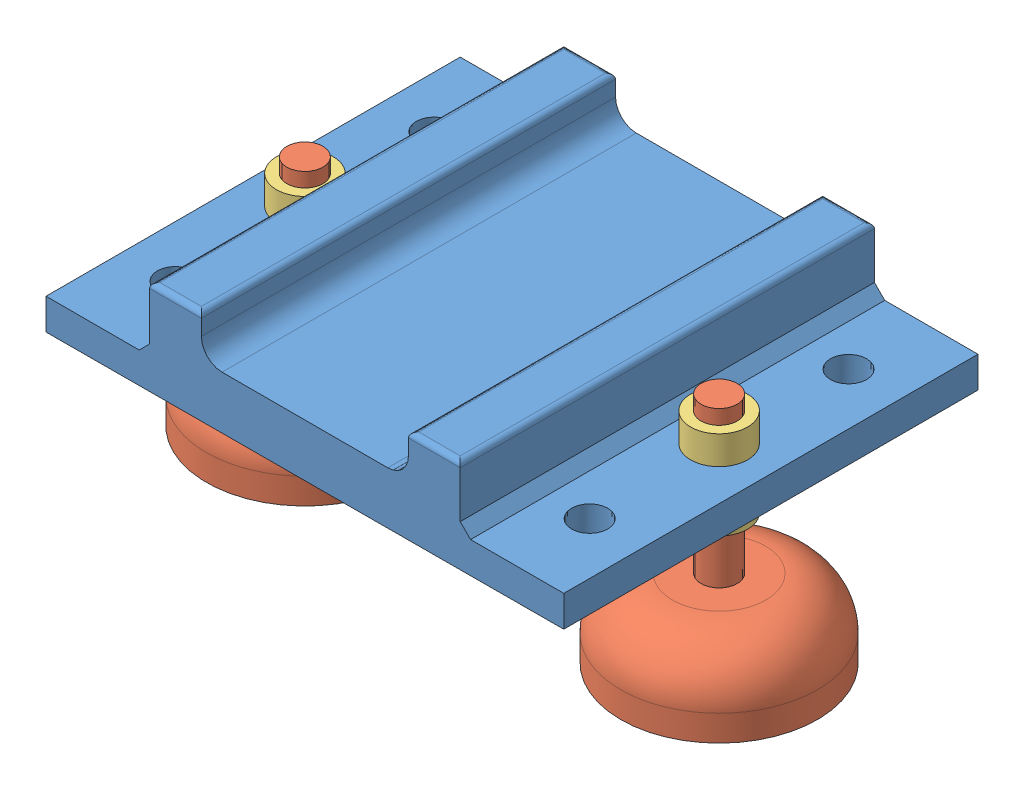
SolidWorks assembly Assemblage1, configuration Défaut. Lengths in mm.
Overall size (129.85 48.97 80).
7 component instances, 3 part files, 6 mates.
Components (placement in the parent):
- piece_maintient_entre_rail-1: piece_maintient_entre_rail [Défaut] at (-82.9065 21.2773 40) size (100 18.3 80)
- Pied-1: Pied [Défaut] at (-92.9065 17.3122 0) x (0.900255 0 -0.435364) z (0.435364 0 0.900255) size (38 45 38)
- Pied-2: Pied [Défaut] at (-12.9065 17.6532 0) x (0.935976 0 -0.352064) z (0.352064 0 0.935976) size (38 45 38)
- ecrou_M7-1: ecrou_M7 [Défaut] at (-92.9065 9.05 0) x (0.995992 0 -0.089439) z (0.089439 0 0.995992) size (11 5.5 11)
- ecrou_M7-2: ecrou_M7 [Défaut] at (-92.9065 -2.574 0) x (0.999221 0 0.039466) z (-0.039466 0 0.999221) size (11 5.5 11)
- ecrou_M7-3: ecrou_M7 [Défaut] at (-12.9065 9.3498 0) x (0.999844 0 -0.017652) z (0.017652 0 0.999844) size (11 5.5 11)
- ecrou_M7-4: ecrou_M7 [Défaut] at (-12.9065 -2.2533 0) x (0.99851 0 -0.054578) z (0.054578 0 0.99851) size (11 5.5 11)
Mates (geometry in assembly coordinates):
- Coaxiale2: concentric: circle of piece_maintient_entre_rail-1; circle of Pied-1
- Coaxiale3: concentric: circle of piece_maintient_entre_rail-1; circle of Pied-2
- Coaxiale4: concentric: circle of Pied-1; circle of ecrou_M7-1
- Coaxiale5: concentric: circle of Pied-1; circle of ecrou_M7-2
- Coaxiale6: concentric: circle of Pied-2; circle of ecrou_M7-3
- Coaxiale7: concentric: circle of ecrou_M7-3; circle of ecrou_M7-4
